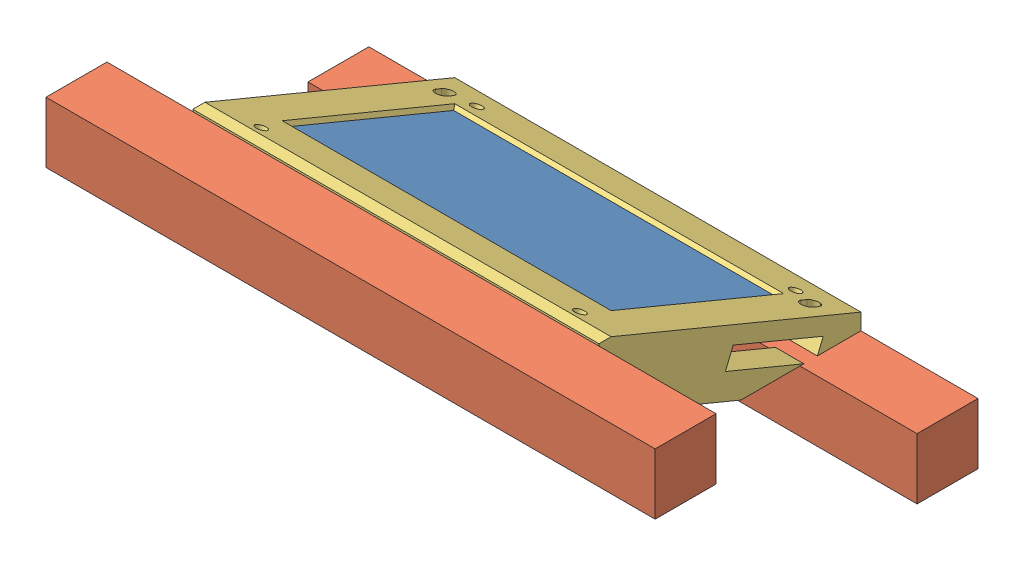
SolidWorks assembly Ensamblaje1, configuration Default. Lengths in mm.
Overall size (300 89 159).
4 component instances, 3 part files, 8 mates.
Components (placement in the parent):
- pantalla lcd-1: pantalla lcd [Predeterminado] at (-6.1915 41.4874 55.9571) x (1 0 0) z (0 0.383015 0.923742) size (165 8.4 123.5)
- perfil 30 roborescue-1: perfil 30 roborescue [Default] at origin size (300 30 30)
- perfil 30 roborescue-2: perfil 30 roborescue [Default] at (0 58 129) size (300 30 30)
- Pieza3-1: Pieza3 [Default] at (-7.6915 59 129) x (1 0 0) z (0 1 0) size (200 136 59)
Mates (geometry in assembly coordinates):
- Coincidente1: coincident aligned: plane of perfil 30 roborescue-1 through (-150 0 0) normal (-1 0 0); plane of perfil 30 roborescue-2 through (-150 58 129) normal (-1 0 0)
- Distancia2: distance = 28 mm anti-aligned: plane of perfil 30 roborescue-2 through (150 43 144) normal (0 -1 0); plane of perfil 30 roborescue-1 through (150 15 15) normal (0 1 0)
- Distancia3: distance = 99 mm anti-aligned: plane of perfil 30 roborescue-2 through (150 73 114) normal (0 0 -1); plane of perfil 30 roborescue-1 through (150 15 15) normal (0 0 1)
- Coincidente5: coincident anti-aligned: plane of marco-ele-1 through (-547.8025 144.0888 3.2541) normal (0 1 0); plane of pantalla lcd-1 through (73.3085 20.4633 1.0744) normal (0 0.923742 -0.383015)
- Coincidente8: coincident anti-aligned: plane of perfil 30 roborescue-1 through (150 15 15) normal (0 1 0); plane of Pieza3-1 through (92.3085 15 -15) normal (0 -1 0)
- Coincidente10: coincident anti-aligned: plane of pantalla lcd-1 through (73.3085 20.4633 1.0744) normal (0 0.923742 -0.383015); plane of Pieza3-1 through (-7.6915 71.3776 123.8678) normal (0 -0.923742 0.383015)
- Coincidente11: coincident anti-aligned: plane of pantalla lcd-1 through (-88.6915 67.6124 97.0332) normal (0 0.383015 0.923742); plane of Pieza3-1 through (-90.6915 61.331 99.6377) normal (0 -0.383015 -0.923742)
- Ancho2: width anti-aligned: plane of Pieza3-1 through (78.3085 21.8805 4.4923) normal (-1 0 0); plane of pantalla lcd-1 through (-90.6915 21.8805 4.4923) normal (1 0 0); plane of Pieza3-1 through (76.3085 65.4676 109.6141) normal (1 0 0); plane of pantalla lcd-1 through (-88.6915 65.4676 109.6141) normal (-1 0 0)
